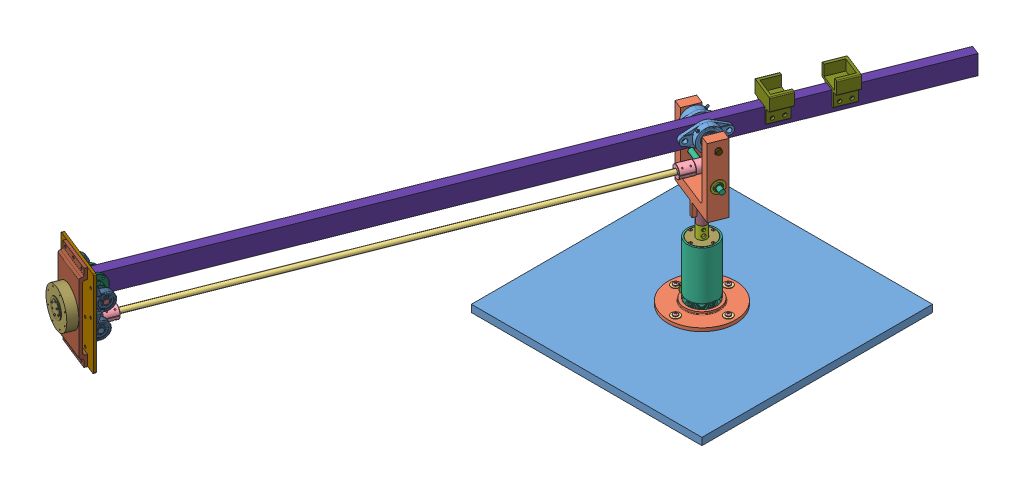
SolidWorks assembly 00_Full Planarizer Assembly, configuration Default. Lengths in mm.
Overall size (865.32 492.39 1808.36).
69 component instances, 34 part files, 7 mates.
Components (placement in the parent):
- 00_01_Base_Assembly-1: 00_01_Base_Assembly [Default] at origin size (609.6 258.13 609.6) (flexible)
  - 00_01_01_Base_Plate-2: 00_01_01_Base_Plate [Default] at (304.8 -19.05 304.8) x (0 0 -1) z (1 0 0) size (609.6 19.05 609.6)
  - 00_01_02_Base_Flange-1: 00_01_02_Base_Flange [Default] at origin size (177.8 15.35 177.8)
  - 00_01_03_91090A107_Zinc-Plated Steel Oversized Washer-2: 00_01_03_91090A107_Zinc-Plated Steel Oversized Washer [91090A107] at (0 10.0584 -69.85) x (0 -1 0) z (0 0 1) size (1.3 22.23 22.23)
  - 00_01_03_91090A107_Zinc-Plated Steel Oversized Washer-1: 00_01_03_91090A107_Zinc-Plated Steel Oversized Washer [91090A107] at (0 10.0584 69.85) x (0 -1 0) z (0 0 -1) size (1.3 22.23 22.23)
  - 00_01_03_91090A107_Zinc-Plated Steel Oversized Washer-3: 00_01_03_91090A107_Zinc-Plated Steel Oversized Washer [91090A107] at (69.85 10.0584 0) x (0 -1 0) z (0 0 -1) size (1.3 22.23 22.23)
  - 00_01_03_91090A107_Zinc-Plated Steel Oversized Washer-4: 00_01_03_91090A107_Zinc-Plated Steel Oversized Washer [91090A107] at (-69.85 10.0584 0) x (0 -1 0) z (0 0 -1) size (1.3 22.23 22.23)
  - 00_01_04_91772A543_Passivated 18-8 Stainless Steel Pan Head Phillips Screw-1: 00_01_04_91772A543_Passivated 18-8 Stainless Steel Pan Head Phillips Screw [91772A543] at (0 -18.5166 69.85) x (-1 0 0) z (0 1 0) size (12.5 12.5 33.12)
  - 00_01_04_91772A543_Passivated 18-8 Stainless Steel Pan Head Phillips Screw-2: 00_01_04_91772A543_Passivated 18-8 Stainless Steel Pan Head Phillips Screw [91772A543] at (-69.85 -18.5166 0) x (-1 0 0) z (0 1 0) size (12.5 12.5 33.12)
  - 00_01_04_91772A543_Passivated 18-8 Stainless Steel Pan Head Phillips Screw-3: 00_01_04_91772A543_Passivated 18-8 Stainless Steel Pan Head Phillips Screw [91772A543] at (69.85 -18.5166 0) x (-1 0 0) z (0 1 0) size (12.5 12.5 33.12)
  - 00_01_04_91772A543_Passivated 18-8 Stainless Steel Pan Head Phillips Screw-4: 00_01_04_91772A543_Passivated 18-8 Stainless Steel Pan Head Phillips Screw [91772A543] at (0 -18.5166 -69.85) x (-1 0 0) z (0 1 0) size (12.5 12.5 33.12)
  - 00_01_05_95462A029_Medium-Strength Steel Hex Nut-1: 00_01_05_95462A029_Medium-Strength Steel Hex Nut [95462A029] at (0 -15.4781 69.85) x (1 0 0) z (0 1 0) size (11.11 12.83 6.51)
  - 00_01_05_95462A029_Medium-Strength Steel Hex Nut-2: 00_01_05_95462A029_Medium-Strength Steel Hex Nut [95462A029] at (-69.85 -15.4781 0) x (1 0 0) z (0 -1 0) size (11.11 12.83 6.51)
  - 00_01_05_95462A029_Medium-Strength Steel Hex Nut-3: 00_01_05_95462A029_Medium-Strength Steel Hex Nut [95462A029] at (0 -15.4781 -69.85) x (1 0 0) z (0 1 0) size (11.11 12.83 6.51)
  - 00_01_05_95462A029_Medium-Strength Steel Hex Nut-4: 00_01_05_95462A029_Medium-Strength Steel Hex Nut [95462A029] at (69.85 -15.4781 0) x (1 0 0) z (0 1 0) size (11.11 12.83 6.51)
  - 00_01_05_95462A029_Medium-Strength Steel Hex Nut-5: 00_01_05_95462A029_Medium-Strength Steel Hex Nut [95462A029] at (-14.3863 232.664 -5.7103) x (0.368926 0 -0.929459) z (0.929459 0 0.368926) size (11.11 12.83 6.51)
  - 00_01_05_95462A029_Medium-Strength Steel Hex Nut-6: 00_01_05_95462A029_Medium-Strength Steel Hex Nut [95462A029] at (-14.3863 217.424 -5.7103) x (0.368926 0 -0.929459) z (0.929459 0 0.368926) size (11.11 12.83 6.51)
  - 00_01_06_Fixed_Housing-2: 00_01_06_Fixed_Housing [Default] at (0 28.575 0) x (1 0 0) z (0 -1 0) size (78.23 80.13 152.8)
  - 00_01_07_Base_Shaft-1: 00_01_07_Base_Shaft [Default] at (0 16.764 0) x (-0.863535 0 -0.504289) z (0 1 0) size (31.75 31.75 171.45)
  - 00_01_08_AST_Bearings_R16ZZ-1: 00_01_08_AST_Bearings_R16ZZ [Default] at (0 136.525 0) x (0 1 0) z (0 0 -1) size (12.7 50.8 50.8)
  - 00_01_08_AST_Bearings_R16ZZ-2: 00_01_08_AST_Bearings_R16ZZ [Default] at (0 92.075 0) x (0 1 0) z (0 0 -1) size (12.7 50.8 50.8)
  - 00_01_09_97633A300_External Retaining Ring-1: 00_01_09_97633A300_External Retaining Ring [97633A300] at (0 147.4724 0) x (0 1 0) z (0 0 1) size (1.07 30.68 28.04)
  - 00_01_10_Encoder_Plate-2: 00_01_10_Encoder_Plate [Default] at (0 38.1 0) x (0 0 1) z (1 0 0) size (87.12 6.63 58.67)
  - 00_01_11_92210A161_18-8 Stainless Steel Hex Drive Flat Head Screw-1: 00_01_11_92210A161_18-8 Stainless Steel Hex Drive Flat Head Screw [92210A161] at (0 150.8618 -30.226) x (1 0 0) z (0 1 0) size (7.8 7.8 9.86)
  - 00_01_11_92210A161_18-8 Stainless Steel Hex Drive Flat Head Screw-2: 00_01_11_92210A161_18-8 Stainless Steel Hex Drive Flat Head Screw [92210A161] at (-30.226 150.8618 0) x (1 0 0) z (0 1 0) size (7.8 7.8 9.86)
  - 00_01_11_92210A161_18-8 Stainless Steel Hex Drive Flat Head Screw-3: 00_01_11_92210A161_18-8 Stainless Steel Hex Drive Flat Head Screw [92210A161] at (0 150.8618 30.226) x (1 0 0) z (0 1 0) size (7.8 7.8 9.86)
  - 00_01_11_92210A161_18-8 Stainless Steel Hex Drive Flat Head Screw-5: 00_01_11_92210A161_18-8 Stainless Steel Hex Drive Flat Head Screw [92210A161] at (-5.715 36.4632 9.8987) x (1 0 0) z (0 -1 0) size (7.8 7.8 9.86)
  - 00_01_11_92210A161_18-8 Stainless Steel Hex Drive Flat Head Screw-6: 00_01_11_92210A161_18-8 Stainless Steel Hex Drive Flat Head Screw [92210A161] at (0 36.4632 30.226) x (1 0 0) z (0 -1 0) size (7.8 7.8 9.86)
  - 00_01_11_92210A161_18-8 Stainless Steel Hex Drive Flat Head Screw-7: 00_01_11_92210A161_18-8 Stainless Steel Hex Drive Flat Head Screw [92210A161] at (30.226 36.4632 0) x (1 0 0) z (0 -1 0) size (7.8 7.8 9.86)
  - 00_01_11_92210A161_18-8 Stainless Steel Hex Drive Flat Head Screw-8: 00_01_11_92210A161_18-8 Stainless Steel Hex Drive Flat Head Screw [92210A161] at (0 36.4632 -30.226) x (1 0 0) z (0 -1 0) size (7.8 7.8 9.86)
  - 00_01_11_92210A161_18-8 Stainless Steel Hex Drive Flat Head Screw-4: 00_01_11_92210A161_18-8 Stainless Steel Hex Drive Flat Head Screw [92210A161] at (30.226 150.8618 0) x (1 0 0) z (0 1 0) size (7.8 7.8 9.86)
  - 00_01_12_Cover_Plate-1: 00_01_12_Cover_Plate [Default] at (0 149.225 0) size (66.55 6.63 66.55)
  - 00_01_13_Base_Adapter-1: 00_01_13_Base_Adapter [Slot_and_Screw_Top] at (0 239.014 0) x (-0.929459 0 -0.368926) z (0.368926 0 -0.929459) size (25.4 63.5 25.4)
  - 00_01_14_1220_91259A582_Alloy Steel Shoulder Screw-1: 00_01_14_1220_91259A582_Alloy Steel Shoulder Screw [91259A582] at (16.9684 232.664 6.7352) x (0.368926 0 -0.929459) z (0.929459 0 0.368926) size (11.11 11.11 39.65) (hidden)
  - 00_01_14_1220_91259A582_Alloy Steel Shoulder Screw-2: 00_01_14_1220_91259A582_Alloy Steel Shoulder Screw [91259A582] at (16.9684 217.424 6.7352) x (0.368926 0 -0.929459) z (0.929459 0 0.368926) size (11.11 11.11 39.65)
  - 00_01_15_SlipRing-1: 00_01_15_SlipRing [Default] at (0 41.2257 0) size (54 38.66 54)
  - 00_01_16_E6-X-500-X-D-H-D-X-1: 00_01_16_E6-X-500-X-D-H-D-X [Default] at (0 31.75 0) x (0 0 -1) z (-1 0 0) size (56.39 16.59 76.2)
- BoomAssembly-1: BoomAssembly [Unmovable Boom] at (0 400.939 0) x (0.929459 0 0.368926) z (-0.368926 0 0.929459) size (175.16 266.08 1876.08)
  - Aluminium Beam^BoomAssembly-1: Aluminium Beam^BoomAssembly [Default] at (0 0 -556.5902) size (25.4 55.63 1828.8) (virtual)
  - BeamHubShaft^BoomAssembly-1: BeamHubShaft^BoomAssembly [Default] at (28.4587 -556.2205 20.2836) x (0 -0.999336 0.036443) z (1 0 0) size (12.7 12.7 149.86) (virtual)
  - UCFL201-8-TheTimkenCompany-3D-09-18-2023 (1).stp-1: UCFL201-8-TheTimkenCompany-3D-09-18-2023 (1).stp [Default] at (-12.7 0 0) x (0 0 1) z (0 1 0) size (113 33.3 60)
  - UCFL201-8-TheTimkenCompany-3D-09-18-2023 (1).stp-2: UCFL201-8-TheTimkenCompany-3D-09-18-2023 (1).stp [Default] at (12.7 0 0) x (0 0 -1) z (0 1 0) size (113 33.3 60)
  - Yoke^BoomAssembly-1: Yoke^BoomAssembly [Default] x (-1 0 0) z (0 0 -1) size (152.4 215.9 44.45) (virtual)
  - 00_03_Boom_Assembly-1: 00_03_Boom_Assembly [Default] at (0 -82.55 1231.4237) x (1 0 0) z (0 0 -1) size (178.38 31.75 1278.52)
    - 00_03_01_Boom-1: 00_03_01_Boom [Default] at origin size (12.7 12.7 1219.2)
    - 00_03_02_Boom_Shaft_End-1: 00_03_02_Boom_Shaft_End [3463N51] at (0 0 5.5563) size (31.71 31.75 69.85)
    - 00_03_02_Boom_Shaft_End-2: 00_03_02_Boom_Shaft_End [3463N51] at (0 0 1213.6437) x (-1 0 0) z (0 0 -1) size (31.71 31.75 69.85)
    - 00_03_03_92313A576_Super-Corrosion-Resistant Cup-Point Set Screw-1: 00_03_03_92313A576_Super-Corrosion-Resistant Cup-Point Set Screw [92313A576] at (0 0 -25.2586) x (-1 0 0) z (0 0 -1) size (8.13 8.07 10.1)
    - 00_03_03_92313A576_Super-Corrosion-Resistant Cup-Point Set Screw-2: 00_03_03_92313A576_Super-Corrosion-Resistant Cup-Point Set Screw [92313A576] at (0 0 1230.8713) size (8.13 8.07 10.1)
    - Carbon Support Shaft^00_03_Boom_Assembly-1: Carbon Support Shaft^00_03_Boom_Assembly [Default] at (0 0 1231.4237) size (172.03 12.7 12.7) (virtual)
  - 6383K234_Ball Bearing-1: 6383K234_Ball Bearing [6383K234] at (72.9615 -82.55 0) x (0 0.082275 0.99661) z (-1 0 0) size (31.75 31.75 11.13)
  - 6383K234_Ball Bearing-2: 6383K234_Ball Bearing [6383K234] at (-72.9615 -82.55 0) x (0 0.309512 -0.950895) z (1 0 0) size (31.75 31.75 11.13)
  - 90030A101_Heavy Duty External Retaining Ring-1: 90030A101_Heavy Duty External Retaining Ring [90030A101] at (76.95 0 0) x (0 -0.307561 -0.951528) z (1 0 0) size (13.48 16.2 1.5)
  - 90030A101_Heavy Duty External Retaining Ring-2: 90030A101_Heavy Duty External Retaining Ring [90030A101] at (80.0742 -82.55 0) x (0 0 -1) z (1 0 0) size (13.48 16.2 1.5)
  - Knuckle-1: Knuckle [Default] at (0 0.0034 1265.8348) x (0 0.000154 1) z (-1 0 0) size (97.43 227.33 152.1)
    - Knuckle Plate^Knuckle-1: Knuckle Plate^Knuckle [Default] at origin size (6.35 227.33 152) (virtual)
    - 5913K61_Low-Profile Mounted Sealed Steel Ball Bearing-1: 5913K61_Low-Profile Mounted Sealed Steel Ball Bearing [5913K61] at (-22.2 0 -63.5) x (0 1 0) z (0 0 1) size (86.1 44.81 28.6)
    - 5913K61_Low-Profile Mounted Sealed Steel Ball Bearing-3: 5913K61_Low-Profile Mounted Sealed Steel Ball Bearing [5913K61] at (-22.2 0 63.5) x (0 -1 0) z (0 0 -1) size (86.1 44.81 28.6)
    - 5913K61_Low-Profile Mounted Sealed Steel Ball Bearing-4: 5913K61_Low-Profile Mounted Sealed Steel Ball Bearing [5913K61] at (-22.2 -82.55 -38.1) x (0 1 0) z (0 0 1) size (86.1 44.81 28.6)
    - 5913K61_Low-Profile Mounted Sealed Steel Ball Bearing-6: 5913K61_Low-Profile Mounted Sealed Steel Ball Bearing [5913K61] at (-22.2 -82.55 38.1) x (0 -1 0) z (0 0 -1) size (86.1 44.81 28.6)
    - 00_04_01_CANSide mount-1: 00_04_01_CANSide mount [Default] at (16.51 -127 0) x (-1 0 0) z (0 0 -1) size (17.78 227.33 99.06)
    - CE_AK80-6_Model-1: CE_AK80-6_Model [AliExpress (2.5mm)] at (24.13 -41.275 0) x (0 -1 0) z (0 0 1) size (98 40.5 98)
    - Copy of Carbon Support Shaft^Knuckle-1: Copy of Carbon Support Shaft^Knuckle [Default] at (-22.2 0 0) x (0 0 -1) z (1 0 0) size (142.17 12.7 12.7) (virtual)
    - Copy of Copy of Carbon Support Shaft^Knuckle-1: Copy of Copy of Carbon Support Shaft^Knuckle [Default] at (-22.2 -82.55 0) x (0 0 -1) z (-1 0 0) size (91.38 12.7 12.7) (virtual)
  - 1870K3_Easy-Access Flange-Mounted Shaft Support-1: 1870K3_Easy-Access Flange-Mounted Shaft Support [1870K3] at (38.1 0 1243.6348) x (0 -0.707107 -0.707107) z (0 0.707107 -0.707107) size (57.15 25.4 57.15)
  - 1870K3_Easy-Access Flange-Mounted Shaft Support-2: 1870K3_Easy-Access Flange-Mounted Shaft Support [1870K3] at (-38.1 0.2187 1243.8915) x (0 0.707107 0.707107) z (0 0.707107 -0.707107) size (57.15 25.4 57.15)
  - Battery Holder-1: Battery Holder [Default] at (0 25.4 -216.2859) x (-1 0 0) z (0 0 -1) size (69.05 72.45 187.7)
    - Part1^Battery Holder-1: Part1^Battery Holder [Default] at (0 0 -93.85) size (69.05 72.45 50.8) (virtual)
    - Part1^Battery Holder-3: Part1^Battery Holder [Default] at (0 0 93.85) x (-1 0 0) z (0 0 -1) size (69.05 72.45 50.8) (virtual)
Mates (geometry in assembly coordinates):
- Coincident1: coordinate: point of 00_01_Base_Assembly-1/00_01_02_Base_Flange-1
- Coincident2: coincident anti-aligned: plane of 00_02_Holder_Assembly^00_Full Planarizer Assembly-1 through (0 207.264 0) normal (0.150135 0 0.988666); plane of 00_01_Base_Assembly-1/00_01_13_Base_Adapter-1 through (0 239.014 0) normal (0.368926 0 -0.929459)
- Coincident4: coincident aligned: plane of 00_01_Base_Assembly-1/00_01_13_Base_Adapter-1 through (0 207.264 0) normal (0 1 0); plane of 00_02_Holder_Assembly^00_Full Planarizer Assembly-1 through (0 207.264 0) normal (0 1 0)
- Coincident5: coincident aligned: plane of 00_01_Base_Assembly-1/00_01_13_Base_Adapter-1 through (0 239.014 0) normal (-0.929459 0 -0.368926); plane of 00_02_Holder_Assembly^00_Full Planarizer Assembly-1 through (0 207.264 0) normal (-0.988666 0 0.150135)
- Coincident6: coincident aligned: plane of 00_01_Base_Assembly-1/00_01_13_Base_Adapter-1 through (0 239.014 0) normal (-0.929459 0 -0.368926); plane of BoomAssembly-1/Yoke^BoomAssembly-1 through (0 400.939 0) normal (-0.929459 0 -0.368926)
- Coincident9: coincident aligned: plane of 00_01_Base_Assembly-1/00_01_13_Base_Adapter-1 through (0 239.014 0) normal (0.368926 0 -0.929459); plane of BoomAssembly-1/Yoke^BoomAssembly-1 through (0 400.939 0) normal (0.368926 0 -0.929459)
- Coincident10: coincident anti-aligned: plane of 00_01_Base_Assembly-1/00_01_13_Base_Adapter-1 through (0 207.264 0) normal (0 1 0); plane of BoomAssembly-1/Yoke^BoomAssembly-1 through (3.7728 207.264 -22.4142) normal (0 -1 0)
